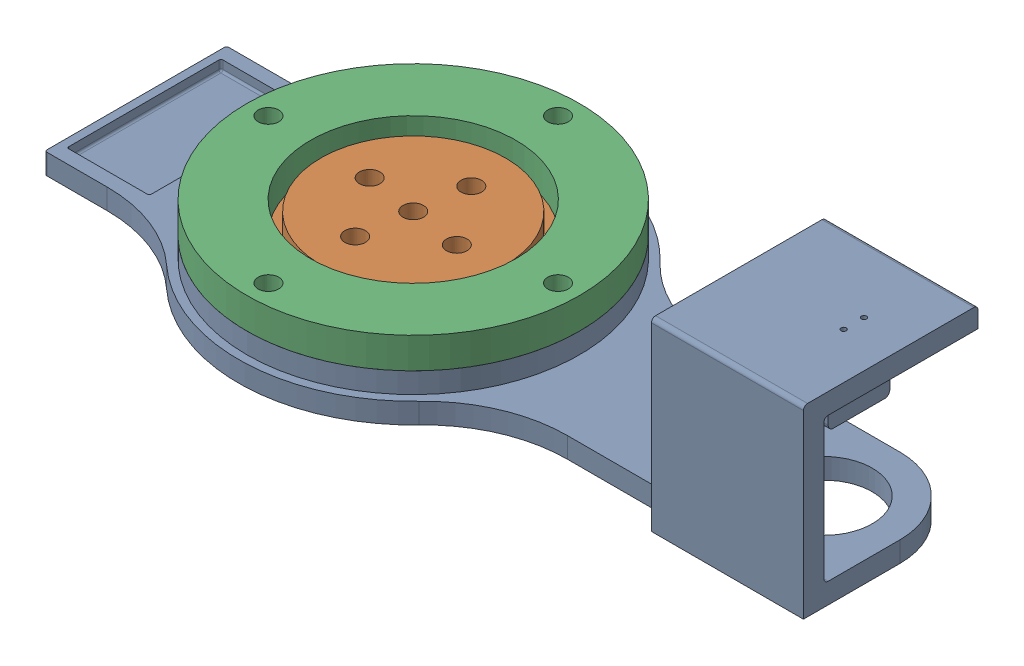
SolidWorks assembly Primer Eslabon - Ensamblaje, configuration Predeterminado. Lengths in mm.
Overall size (372.14 90 170).
3 component instances, 3 part files, 6 mates.
Components (placement in the parent):
- Primer Eslabon - E1.2-1: Primer Eslabon - E1.2 [Predeterminado] at (-45.7751 -16.6571 85) size (372.14 90 170)
- Eje de rotacion - E1.1-1: Eje de rotacion - E1.1 [Predeterminado] at (-45.7751 -16.6571 85) x (0.989986 0 0.141165) z (-0.141165 0 0.989986) size (120 30 120)
- Cubierta Eje - E1.3-1: Cubierta Eje - E1.3 [Predeterminado] at (-45.7751 18.3429 85) x (1 0 0) z (0 -1 0) size (162 162 15)
Mates (geometry in assembly coordinates):
- Concéntrica1: concentric aligned: cylinder of Primer Eslabon - P1.1-1 through (-45.7751 3.3429 85) axis (0 -1 0) radius 60; cylinder of plato-PL-1 through (-45.7751 13.3429 85) axis (0 -1 0) radius 45
- Concéntrica2: concentric anti-aligned: cylinder of plato-PL-1 through (-45.7751 13.3429 85) axis (0 -1 0) radius 45; cylinder of TAPApaleta1-P1.2-1 through (-45.7751 3.3429 85) axis (0 1 0) radius 50
- Coincidente1: coincident anti-aligned: plane of Primer Eslabon - P1.1-1 through (-45.7751 -6.6571 85) normal (0 1 0); plane of plato-PL-1 through (-45.7751 -6.6571 85) normal (0 -1 0)
- Concéntrica3: concentric anti-aligned: cylinder of Primer Eslabon - P1.1-1 through (-45.7751 -30.7993 155.5) axis (0 1 0) radius 5; cylinder of TAPApaleta1-P1.2-1 through (-45.7751 32.485 155.5) axis (0 -1 0) radius 5
- Concéntrica4: concentric anti-aligned: cylinder of Primer Eslabon - P1.1-1 through (-45.7751 -30.7993 14.5) axis (0 1 0) radius 5; cylinder of TAPApaleta1-P1.2-1 through (-45.7751 32.485 14.5) axis (0 -1 0) radius 5
- Coincidente2: coincident anti-aligned: plane of Primer Eslabon - P1.1-1 through (-45.7751 3.3429 85) normal (0 1 0); plane of TAPApaleta1-P1.2-1 through (-45.7751 3.3429 85) normal (0 -1 0)
